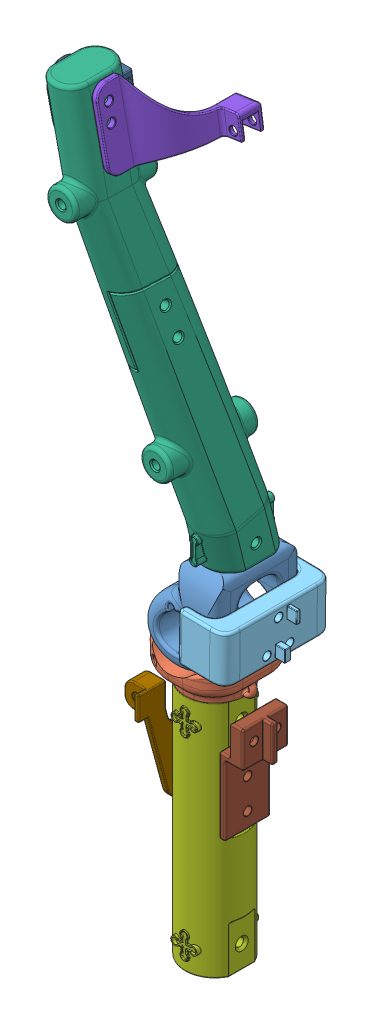
SolidWorks assembly Assem2.51_test_with_patella_sketch, configuration Default. Lengths in mm.
Overall size (210.3 672.28 0).
11 component instances, 11 part files, 30 mates.
Components (placement in the parent):
- Femoral end with hardware - bone connection-1: Femoral end with hardware - bone connection [Default] at (8.0279 -64.5915 6.35) x (-1 0 0) z (0 0 -1) size (73.59 126.4 79.28) (hidden)
- Tibial head with hardware - bone connection-1: Tibial head with hardware - bone connection [Default] at (606.9 33.6817 348.343) x (0 0 1) z (-1 0 0) size (75.94 98.43 76.39) (hidden)
- New link 1-1: New link 1 [Default] at (17.1877 -33.9748 -6.35) x (0.892313 0.451418 0) z (0 0 1) size (12.7 64.13 6.35) (hidden)
- Split link 2-2: Split link 2 [Default] at (8 -24.3417 0) x (-0.681265 0.732037 0) z (0 0 1) size (12.7 59.56 6.35) (hidden)
- Patella_v3_template-1: Patella_v3_template [Default] at (54.2108 10.6202 0) x (0.9999 -0.01417 0) z (0 0 1) size (48 39.5 92.87) (hidden)
- Femur-1: Femur [Default] at (-4.5 395.8 0) size (91.18 361.77 133) (hidden)
- Tibia-1: Tibia [Default] at (0.1087 -68.7561 -0.5365) size (50 268.76 52.05) (hidden)
- Vastus_brkt_origin-1: Vastus_brkt_origin [Default] at (-4.5 395.8 0) size (56.51 72.89 93.84) (hidden)
- BifemSH_brkt_insertion-1: BifemSH_brkt_insertion [Side clamp] at (-16.5255 -47.1661 -0.5365) size (20 90.14 52) (hidden)
- BifemSH_brkt_origin-1: BifemSH_brkt_origin [Default] at (-4.5 395.8 0) size (19.79 52.89 64.84) (hidden)
- Tibia_vastus_brkt-1: Tibia_vastus_brkt [M6 clamps] at (-16.5255 -47.1661 -0.5365) size (28 88.4 38.1) (hidden)
Mates (geometry in assembly coordinates):
- Coincident33: coincident: point of Femoral end with hardware - bone connection-1
- Concentric9: concentric anti-aligned: cylinder of Femoral end with hardware - bone connection-1 through (0 0 -36.83) axis (0 0 1) radius 3.175; cylinder of New link 1-1 through (0 0 0) axis (0 0 -1) radius 3.937
- Concentric10: concentric anti-aligned: cylinder of Tibial head with hardware - bone connection-1 through (23.2187 -45.8961 -38.0365) axis (0 0 1) radius 3.175; cylinder of New link 1-1 through (23.2187 -45.8961 0) axis (0 0 -1) radius 3.937
- Coincident6: coincident anti-aligned: plane of Tibial head with hardware - bone connection-1 through (29.5687 -26.8461 -6.35) normal (0 0 1); plane of New link 1-1 through (0 0 -6.35) normal (0 0 -1)
- Distance1: distance = 1.524 mm anti-aligned: plane of Femoral end with hardware - bone connection-1 through (0 0 -7.874) normal (0 0 1); plane of New link 1-1 through (0 0 -6.35) normal (0 0 -1)
- Concentric14: concentric aligned: cylinder of Femoral end with hardware - bone connection-1 through (17.78 -15.24 33.655) axis (0 0 -1) radius 3.175; cylinder of Split link 2-2 through (17.78 -15.24 6.35) axis (0 0 -1) radius 3.937
- Concentric15: concentric aligned: cylinder of Femoral end with hardware - bone connection-1 through (17.78 -15.24 33.655) axis (0 0 -1) radius 3.175; cylinder of Split link 2-2 through (17.78 -15.24 6.35) axis (0 0 -1) radius 3.937
- Concentric16: concentric anti-aligned: cylinder of Tibial head with hardware - bone connection-1 through (-16.5255 -47.1661 -38.0365) axis (0 0 1) radius 3.175; cylinder of Split link 2-2 through (-16.5255 -47.1661 6.35) axis (0 0 -1) radius 3.937
- Coincident29: coincident anti-aligned: plane of Femoral end with hardware - bone connection-1 through (-35.0492 -54.4464 6.35) normal (0 0 -1); plane of Split link 2-2 through (-16.5255 -47.1661 6.35) normal (0 0 1)
- Distance2: distance = 16.3 mm aligned: plane of Patella_v3_template-1 through (54.2108 10.6202 45) normal (0.9999 -0.01417 0); plane of Femoral end with hardware - bone connection-1 through (37.441 -22.4095 36.83) normal (0.9999 -0.01417 0)
- Coincident31: coincident aligned: plane of New link 1-1 through (0 0 0) normal (0 0 1); plane of Patella_v3_template-1 through (54.2108 10.6202 0) normal (0 0 1)
- Angle1: planar angle = 0 rad aligned: plane of Femoral end with hardware - bone connection-1 through (29.2802 26.9995 7.8899) normal (1 0 0); plane of assembly through (0 0 0) normal (1 0 0)
- Distance3: distance = 395.8 mm aligned: plane of Femur-1 through (-4.5 395.8 0) normal (0 1 0)
- Distance4: distance = 4.5 mm aligned: plane of Femur-1 through (-4.5 395.8 0) normal (1 0 0)
- Distance8: distance = 0 mm aligned: plane of Femur-1 through (-4.5 395.8 0) normal (0 0 1)
- Parallel6: parallel anti-aligned: plane of assembly through (0 0 0) normal (0 0 1); plane of Femoral end with hardware - bone connection-1 through (-35.0492 -54.4464 6.35) normal (0 0 -1)
- Parallel8: parallel aligned: cylinder of Tibial head with hardware - bone connection-1 through (-40.4328 -87.8061 -0.5365) axis (1 0 0) radius 3.175; cylinder of Tibia-1 through (-24.8913 -87.8061 -0.5365) axis (1 0 0) radius 3.45
- Concentric21: concentric aligned: cylinder of Tibial head with hardware - bone connection-1 through (-40.4328 -87.8061 -0.5365) axis (1 0 0) radius 3.175; cylinder of Tibia-1 through (-24.8913 -87.8061 -0.5365) axis (1 0 0) radius 3.45
- Coincident40: coincident anti-aligned: plane of Tibial head with hardware - bone connection-1 through (0.3587 -68.7561 -0.5365) normal (0 -1 0); plane of Tibia-1 through (0.1087 -68.7561 -0.5365) normal (0 1 0)
- Coincident41: coincident anti-aligned: plane of Tibial head with hardware - bone connection-1 through (13.0587 -106.8561 12.1635) normal (1 0 0); plane of Tibia-1 through (13.0587 -107.5561 -13.4865) normal (-1 0 0)
- Angle2: planar angle = 0 rad aligned: plane of Tibia-1 through (22.6087 -68.7561 -26.5365) normal (1 0 0); plane of Femoral end with hardware - bone connection-1 through (29.2802 26.9995 7.8899) normal (1 0 0)
- Coincident43: coincident: point of Femur-1; point of Vastus_brkt_origin-1
- Coincident44: coordinate: point of Femur-1; point of Vastus_brkt_origin-1
- Coincident45: coincident aligned: plane of Tibia-1 through (0.1087 -68.7561 -0.5365) normal (0 0 1); plane of BifemSH_brkt_insertion-1 through (-16.5255 -47.1661 -0.5365) normal (0 0 1)
- Coincident46: coincident aligned: plane of Tibia-1 through (0.1087 -68.7561 -0.5365) normal (0 0 1); plane of Tibia_vastus_brkt-1 through (-16.5255 -47.1661 -0.5365) normal (0 0 1)
- Coincident49: coincident: unknown of Tibia_vastus_brkt-1
- Coincident50: coincident: unknown of BifemSH_brkt_insertion-1
- Coincident53: coordinate: point of Femur-1; point of BifemSH_brkt_origin-1
- Concentric22: concentric aligned: cylinder of Tibia-1 through (126.1087 -125.9061 -0.5365) axis (-1 0 0) radius 3.45; cylinder of Tibia_vastus_brkt-1 through (27.6087 -125.9061 -0.5365) axis (-1 0 0) radius 3.45
- Concentric23: concentric anti-aligned: cylinder of Tibia-1 through (126.1087 -125.9061 -0.5365) axis (-1 0 0) radius 3.45; cylinder of BifemSH_brkt_insertion-1 through (-27.3913 -125.9061 -0.5365) axis (1 0 0) radius 3.45
